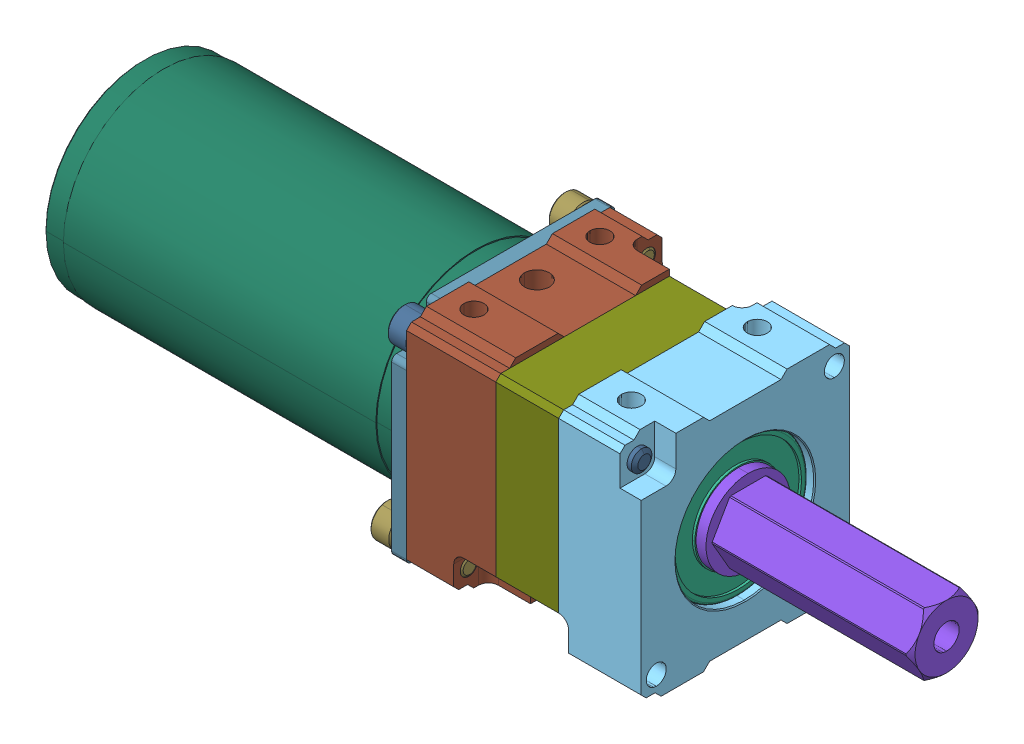
SolidWorks assembly VersaPlanetary v2 Single Stage 10_1 with BAG .step, configuration Default. Lengths in mm.
Overall size (163.4 63.52 63.52).
29 component instances, 19 part files, 0 mates.
Components (placement in the parent):
- 217-2820 Rev1_Public.step-1: 217-2820 Rev1_Public.step [Default] at (-4.6546 22.225 0) x (0 -0.456494 0.889726) z (-1 0 0) size (39.22 38.88 17.4)
  - 217-2625-100.step-1: 217-2625-100.step [Default] at origin size (39.22 38.88 12.7)
    - 217-2625-008 Rev1.step-1: 217-2625-008 Rev1.step [Default] at origin size (34.7 34.7 4.7)
    - 217-2625-010 Rev1.step-1: 217-2625-010 Rev1.step [Default] at (0 10.193 3.65) x (0.999813 0.019336 0) z (0 0 1) size (4 4 12)
    - 217-2625-010 Rev1.step-2: 217-2625-010 Rev1.step [Default] at (8.691 -5.3258 3.65) size (4 4 12)
    - 217-2625-010 Rev1.step-3: 217-2625-010 Rev1.step [Default] at (-8.691 -5.3258 3.65) size (4 4 12)
    - 217-2625-005 Rev1_Planet_Revolving_Follower01.step-1: 217-2625-005 Rev1_Planet_Revolving_Follower01.step [Default] at (8.691 -5.3258 6.35) x (0.932816 0.360354 0) z (0 0 1) size (16.89 16.89 8)
    - 217-2625-005 Rev1_Planet_Revolving_Follower01.step-2: 217-2625-005 Rev1_Planet_Revolving_Follower01.step [Default] at (-8.691 -5.3258 6.35) x (-0.932788 -0.360426 0) z (0 0 1) size (16.89 16.89 8)
    - 217-2625-005 Rev1_Planet_Revolving_Follower01.step-3: 217-2625-005 Rev1_Planet_Revolving_Follower01.step [Default] at (0 10.193 6.35) x (0.893583 0.448898 0) z (0 0 1) size (16.89 16.89 8)
  - 217-2625-007 Rev1_Public.step-1: 217-2625-007 Rev1_Public.step [Default] at (0 0 6.7) x (0.992772 0.120019 0) z (0 0 1) size (15.27 15.27 12.7)
- 217-2625-026 Rev1.step-1: 217-2625-026 Rev1.step [Default] at (-6.5 22.225 0) x (0 -1 0) z (-1 0 0) size (44.45 42 18.12)
- 217-2742-001 Rev4.step-1: 217-2742-001 Rev4.step [Default] at (0.2002 22.225 0) x (1 0 0) z (0 -0.092627 0.995701) size (7 28 28)
- 217-2742-001 Rev4.step-2: 217-2742-001 Rev4.step [Default] at (8.2002 22.225 0) size (7 28 28)
- 217-2625-017 Rev1_9714K61.step-1: 217-2625-017 Rev1_9714K61.step [Default] at (7.42 22.3002 -0.342) x (0 0.56703 0.823697) z (0 -0.823697 0.56703) size (28.51 4.98 27.43)
- 217-2625-003 Rev1.step-1: 217-2625-003 Rev1.step [Default] at (7.4478 22.225 0) x (0 -1 0) z (1 0 0) size (17 17 64.11)
- 217-2625-018 Rev1_98541A410.step-1: 217-2625-018 Rev1_98541A410.step [Default] at (-0.7046 22.225 0) x (1 0 0) z (0 -0.017452 0.999848) size (1 19.6 17.4)
- 832-1750-Ring-Gear-Screw_SSA0832-0500ZC.step-1: 832-1750-Ring-Gear-Screw_SSA0832-0500ZC.step [Default] at (-30.7 4.725 -17.5) x (0 0.997447 0.071411) z (0 -0.071411 0.997447) size (6.73 48.51 6.73)
- 832-1750-Ring-Gear-Screw_SSA0832-0500ZC.step-2: 832-1750-Ring-Gear-Screw_SSA0832-0500ZC.step [Default] at (-30.7 39.725 17.5) x (0 0.005929 0.999982) z (0 -0.999982 0.005929) size (6.73 48.51 6.73)
- 217-2625-025 Rev1.step-1: 217-2625-025 Rev1.step [Default] at (-23.2 22.225 0) x (0 -1 0) z (-1 0 0) size (44.45 42 18)
- 217-4649-002 Rev1_SSA0832-0500ZC.step-1: 217-4649-002 Rev1_SSA0832-0500ZC.step [Default] at (-33.7 4.2645 17.9605) x (0 0.33842 -0.940995) z (0 0.940995 0.33842) size (6.73 16.76 6.73)
- 217-4649-002 Rev1_SSA0832-0500ZC.step-2: 217-4649-002 Rev1_SSA0832-0500ZC.step [Default] at (-33.7 40.1855 -17.9605) x (0 -0.308932 -0.951084) z (0 0.951084 -0.308932) size (6.73 16.76 6.73)
- 217-4649-006 Rev1_SSA0004-008BA.step-1: 217-4649-006 Rev1_SSA0004-008BA.step [Default] at (-30.7 22.225 12.5) x (0 0.5 -0.866025) z (0 -0.866025 -0.5) size (7 14 7)
- 217-4649-006 Rev1_SSA0004-008BA.step-2: 217-4649-006 Rev1_SSA0004-008BA.step [Default] at (-30.7 22.225 -12.5) x (0 -0.5 0.866025) z (0 0.866025 0.5) size (7 14 7)
- 217-2822-003 Rev4.step-1: 217-2822-003 Rev4.step [Default] at (-32.2 22.225 0) x (0 -1 0) z (-1 0 0) size (42 42 4.8)
- 217-3351 Rev2.step-1: 217-3351 Rev2.step [Default] at (-33.7 22.225 0) x (0 0 1) z (1 0 0) size (59.07 59.07 84.5)
- 217-2816-001 Rev1.step-1: 217-2816-001 Rev1.step [Default] at (-6.35 22.225 0) x (0 -1 0) z (1 0 0) size (42 42 14.51)
- 217-4649-001 Rev1.step-1: 217-4649-001 Rev1.step [Default] at (-20.046 22.225 0) x (0 -1 0) z (1 0 0) size (18 18 13)
- 217-4649-007 Rev1_94105A824.step-1: 217-4649-007 Rev1_94105A824.step [Default] at (-25.521 22.225 -6.7835) x (-0.996104 -0.088191 0) z (0 0 -1) size (4.83 4.83 4.77)
- 217-2625-011 Rev1.step-1: 217-2625-011 Rev1.step [Default] at (-24.7818 22.225 0) x (0 0 1) z (0 -1 0) size (8.01 7.5 7.94)
